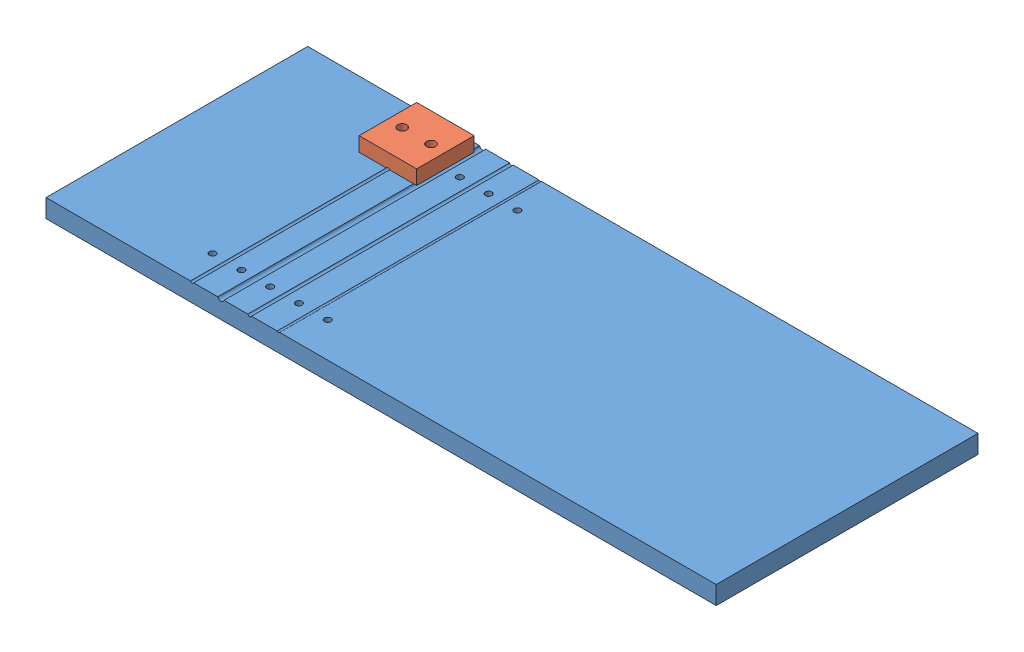
SolidWorks assembly Tube Clamp v-2, configuration Default. Lengths in mm.
Overall size (233 11.35 91.02).
2 component instances, 2 part files, 3 mates.
Components (placement in the parent):
- Tube Clamp v-2-1: Tube Clamp v-2 [Default] at (-58.2425 129.7788 249.9136) size (233 6.35 91.02)
- Tube Clamp 1_24mm top-1: Tube Clamp 1_24mm top [Default] at (36.9329 141.1288 135.3469) x (1 0 0) z (0 0 -1) size (20 5 20)
Mates (geometry in assembly coordinates):
- Coincident1: coincident anti-aligned: plane of Tube Clamp v-2-1 through (-58.2425 136.1288 249.9136) normal (0 1 0); plane of Tube Clamp 1_24mm top-1 through (36.9329 136.1288 135.3469) normal (0 -1 0)
- Concentric1: concentric anti-aligned: circle of Tube Clamp v-2-1; circle of Tube Clamp 1_24mm top-1
- Concentric2: concentric anti-aligned: circle of Tube Clamp v-2-1; circle of Tube Clamp 1_24mm top-1
